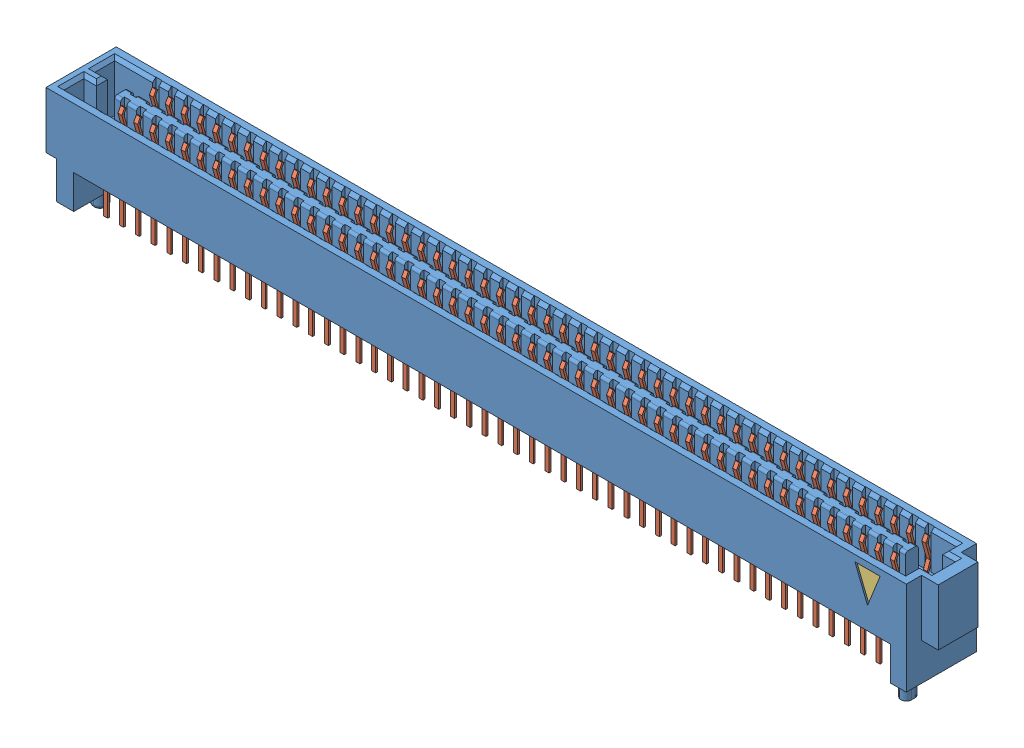
SolidWorks assembly SEAF_50_07_5_L_04_2_A_K_TR, configuration Default. Lengths in mm.
Overall size (70.66 8.81 5.66).
4 component instances, 4 part files, 0 mates.
Components (placement in the parent):
- _SEAF_50_07_5_L_04_1_A_0_K_TR_BODY_2_2-1: _SEAF_50_07_5_L_04_1_A_0_K_TR_BODY_2_2 [Default] at origin size (70.66 8.81 5.66)
- _SEAF_50_07_5_L_04_1_A_0_K_TR_cCON2_4-1: _SEAF_50_07_5_L_04_1_A_0_K_TR_cCON2_4 [Default] at origin size (62.55 7.03 5.41)
- _SEAF_04_K_PAD_6-1: _SEAF_04_K_PAD_6 [Default] at (-0.2286 4.826 0) size (6.5 0.13 6.5) (hidden)
- _SEAF_TRIANGLE_FIRST_PIN_8-1: _SEAF_TRIANGLE_FIRST_PIN_8 [Default] at (30.861 1.27 2.5781) size (2.03 2.54 0.13)
